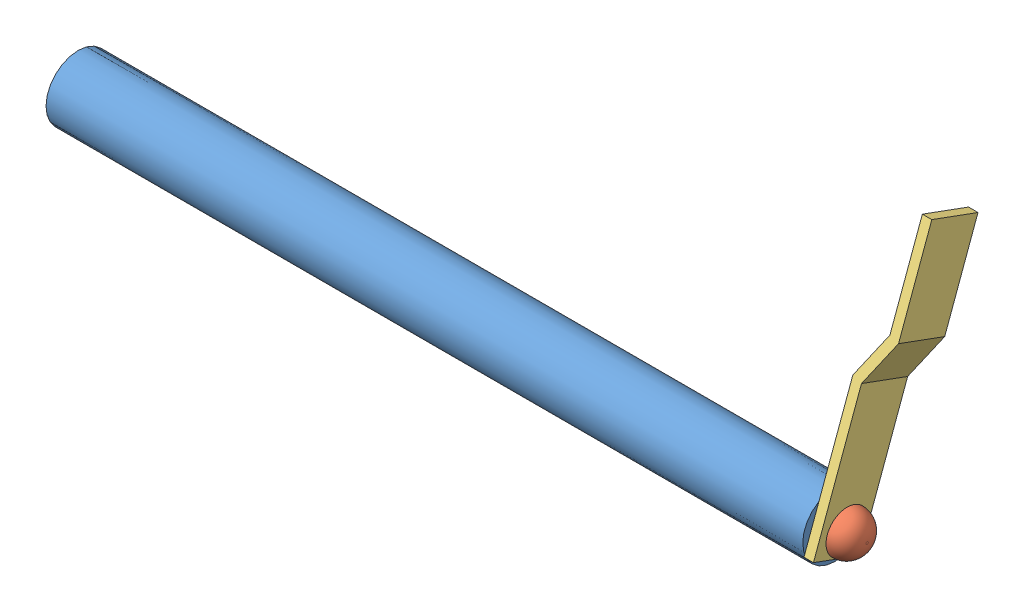
SolidWorks assembly Main Valve 2, configuration Default. Lengths in mm.
Overall size (211.87 75.18 38.39).
3 component instances, 3 part files, 5 mates.
Components (placement in the parent):
- Main Valve Shaft-1: Main Valve Shaft [Default] at (-14.5668 127.1951 189.3128) size (203.2 17.27 17.27)
- Shaft Screw-1: Shaft Screw [Default] at (191.9352 127.1951 189.3128) x (0 -0.383639 -0.923483) z (-1 0 0) size (11.36 11.36 11.68)
- Handle-1: Handle [Default] at (188.6332 119.1851 185.2149) x (0 0.938927 -0.344116) z (1 0 0) size (74.57 13.21 8.67)
Mates (geometry in assembly coordinates):
- Concentric1: concentric anti-aligned: circle of Main Valve Shaft-1; circle of Shaft Screw-1
- Distance2: distance = 3.302 mm anti-aligned: plane of Shaft Screw-1 through (191.9352 127.1951 189.3128) normal (-1 0 0); plane of Main Valve Shaft-1 through (188.6332 127.1951 189.3128) normal (1 0 0)
- Distance3: distance = 0 mm anti-aligned: plane of Handle-1 through (188.6332 123.7302 197.6162) normal (-1 0 0); plane of Main Valve Shaft-1 through (188.6332 127.1951 189.3128) normal (1 0 0)
- Parallel1: parallel anti-aligned: plane of Shaft Screw-1 through (191.9352 127.1951 189.3128) normal (-1 0 0); plane of Handle-1 through (191.1732 123.7302 197.6162) normal (1 0 0)
- Distance5: distance = 0 mm: cylinder of Handle-1 through (197.3031 127.1951 189.3128) axis (-1 0 0) radius 3.048; cylinder of Shaft Screw-1 through (185.5852 127.1951 189.3128) axis (1 0 0) radius 4.3688
